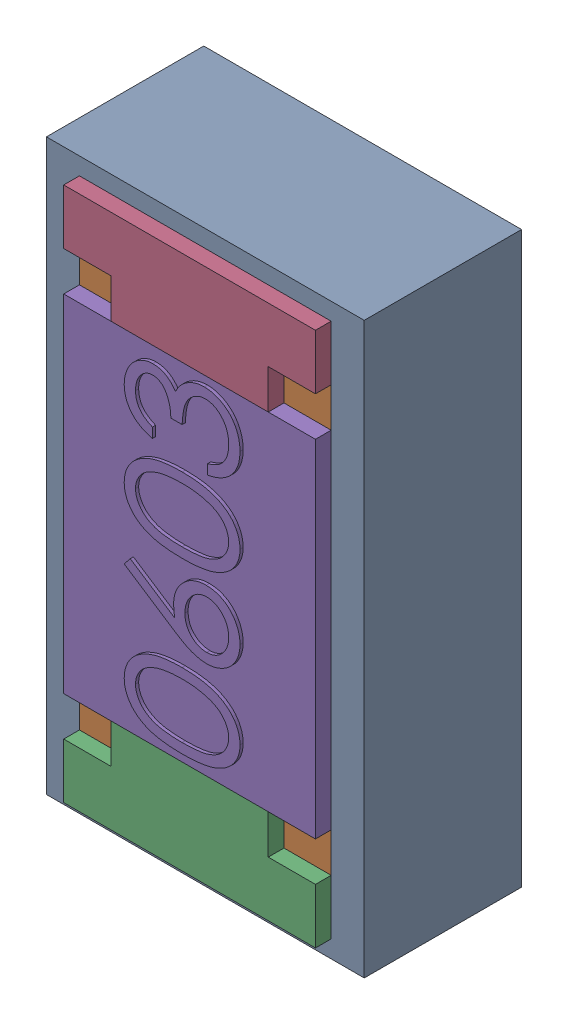
SolidWorks assembly SB4, configuration Default. Lengths in mm.
Overall size (1.01 1.81 0.56).
3 component instances, 2 part files, 0 mates.
Components (placement in the parent):
- 1088884704-1: 1088884704 [Default] at (5 21.425 0) size (1.01 1.81 0.5)
  - Extruded-0-1: Extruded-0 [Default] at origin size (1.01 1.81 0.5)
- R0603-1: R0603 [Default] at (4.9999 21.4251 0) x (0 1 0) z (1 0 0) size (1.7 0.56 0.8)
